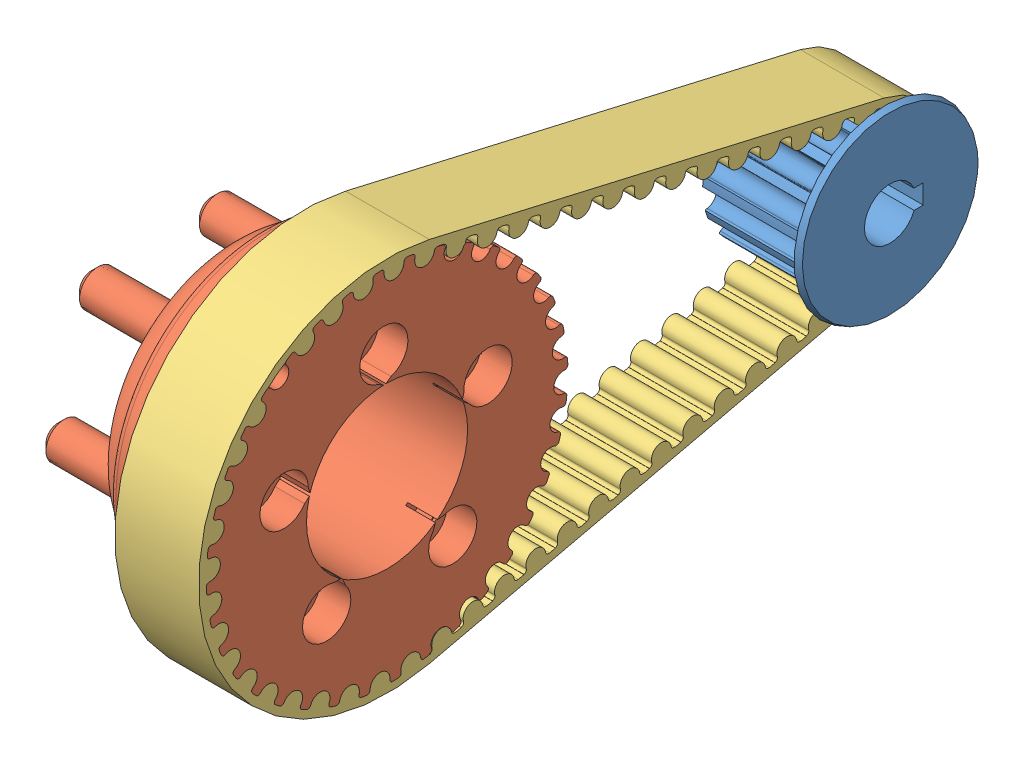
SolidWorks assembly Timing Belt assembly, configuration Default. Lengths in mm.
Overall size (39.93 130.62 133).
4 component instances, 4 part files, 17 mates.
Components (placement in the parent):
- Pulley HTD 5M 15T-1: Pulley HTD 5M 15T [Cut for drawing] at (-10.25 0 0) x (1 0 0) z (0 -0.012224 0.999925) size (17.75 27.96 27.96)
- HTD Parametric Pulley-1: HTD Parametric Pulley [36T 13mm] at (6.5 0 74.34) x (0 0.61209 -0.790788) z (0 0.790788 0.61209) size (56.01 36.18 56.01)
- Teil4^Timing Belt assembly-1: Teil4^Timing Belt assembly [Standard] x (0 0 -1) z (1 0 0) size (114.94 57.3 0) (hidden, virtual)
- Teil5^Timing Belt assembly-1: Teil5^Timing Belt assembly [Standard] at (6.5 0 74.34) x (0 -0.61209 0.790788) z (1 0 0) size (100.6 87.31 13) (virtual)
Mates (geometry in assembly coordinates):
- Symmetrisch1: symmetric aligned: plane of Pulley HTD 5M 15T-1 through (10.25 0 0) normal (1 0 0); plane of Pulley HTD 5M 15T-1 through (-10.25 0 0) normal (-1 0 0)
- Deckungsgleich1: coincident: line of Pulley HTD 5M 15T-1 through (0 15 -7.5) axis (0 0 1)
- Deckungsgleich2: coincident: line of Pulley HTD 5M 15T-1 through (0 15 -7.5) axis (0 0 1)
- Symmetrisch2: symmetric aligned: plane of HTD Parametric Pulley-1 through (6.5 0 74.34) normal (1 0 0); plane of HTD Parametric Pulley-1 through (-6.5 0 74.34) normal (-1 0 0)
- Deckungsgleich3: coincident: axis of HTD Parametric Pulley-1 through (-3.6952 0 74.34) axis (-1 0 0); plane of assembly through (0 0 0) normal (0 1 0)
- Platziert1: in place: plane of ? through (6.5 0 71.8) normal (1 0 0); plane of ? through (6.5 0 0) normal (1 0 0); moOrthogonalPlaneRef_w of ? through (6.5 0 71.8) normal (1 0 0); plane of ? through (6.5 0 0) normal (0 1 0); plane of ? through (6.5 0 71.8) normal (1 0 0); plane of ? through (6.5 0 0) normal (0 0 -1); plane of HTD Parametric Pulley-1 through (6.5 0 74.34) normal (1 0 0); unknown of Teil5^Timing Belt assembly-1
- Deckungsgleich4: coincident aligned: plane of HTD Parametric Pulley-1; plane of ?
- Deckungsgleich5: coincident aligned: moOrthogonalPlaneRef_w of HTD Parametric Pulley-1; plane of Teil2^Timing Belt assembly-1 through (6.5 0 74.34) normal (0 -0.790788 -0.61209)
- Deckungsgleich6: coincident anti-aligned: moOrthogonalPlaneRef_w of HTD Parametric Pulley-1; plane of Teil2^Timing Belt assembly-1 through (6.5 0 74.34) normal (0 -0.61209 0.790788)
- Platziert2: in place: plane of Teil4^Timing Belt assembly-1 through (0 0 0) normal (1 0 0); plane of Teil4^Timing Belt assembly-1 through (0 0 0) normal (0 1 0); plane of Teil4^Timing Belt assembly-1 through (0 0 0) normal (0 0 -1); unknown of Teil4^Timing Belt assembly-1
- Deckungsgleich7: coincident aligned: 
- Deckungsgleich8: coincident aligned: plane of Teil4^Timing Belt assembly-1 through (0 0 0) normal (0 1 0)
- Deckungsgleich9: coincident anti-aligned: plane of Teil4^Timing Belt assembly-1 through (0 0 0) normal (0 0 -1)
- Platziert3: in place: plane of HTD Parametric Pulley-1 through (6.5 0 74.34) normal (1 0 0); plane of ? through (6.5 0 0) normal (1 0 0); plane of HTD Parametric Pulley-1 through (6.5 0 74.34) normal (1 0 0); plane of ? through (6.5 0 0) normal (0 1 0); plane of HTD Parametric Pulley-1 through (6.5 0 74.34) normal (1 0 0); plane of ? through (6.5 0 0) normal (0 0 -1); plane of HTD Parametric Pulley-1 through (6.5 0 74.34) normal (1 0 0); unknown of Teil5^Timing Belt assembly-1
- Deckungsgleich10: coincident aligned: plane of HTD Parametric Pulley-1; plane of Teil5^Timing Belt assembly-1
- Deckungsgleich11: coincident aligned: moOrthogonalPlaneRef_w of HTD Parametric Pulley-1 through (6.5 0 74.34) normal (0 -0.790788 -0.61209); plane of Teil5^Timing Belt assembly-1 through (6.5 0 74.34) normal (0 -0.790788 -0.61209)
- Deckungsgleich12: coincident anti-aligned: moOrthogonalPlaneRef_w of HTD Parametric Pulley-1 through (6.5 0 74.34) normal (0 0.61209 -0.790788); plane of Teil5^Timing Belt assembly-1 through (6.5 0 74.34) normal (0 -0.61209 0.790788)
